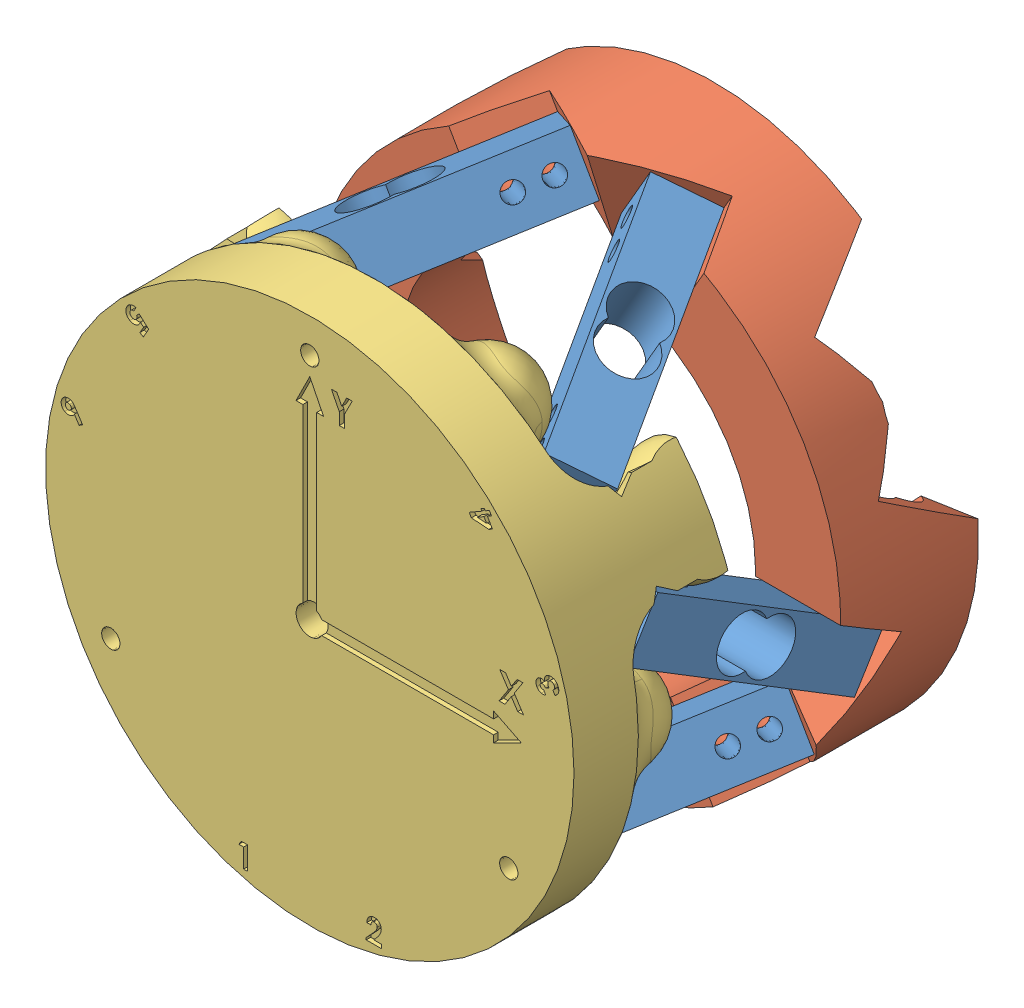
SolidWorks assembly Capteur 6 axes V3, configuration Défaut. Lengths in mm.
Overall size (115 115 88).
8 component instances, 3 part files, 19 mates.
Components (placement in the parent):
- Cellule_2kg-1: Cellule_2kg [Défaut] at (46.7654 0 44) x (1 0 0) z (0 -0.523016 -0.852323) size (12.7 12.7 58)
- Cellule_2kg-2: Cellule_2kg [Défaut] at (23.3827 40.5 44) x (0.5 0.866025 0) z (0.452945 -0.261508 0.852323) size (12.7 12.7 58)
- Cellule_2kg-3: Cellule_2kg [Défaut] at (-23.3827 40.5 44) x (0.5 -0.866025 0) z (-0.452945 -0.261508 0.852323) size (12.7 12.7 58)
- Cellule_2kg-4: Cellule_2kg [Défaut] at (-46.7654 0 44) x (1 0 0) z (0 -0.523016 -0.852323) size (12.7 12.7 58)
- Cellule_2kg-5: Cellule_2kg [Défaut] at (-23.3827 -40.5 44) x (0.5 0.866025 0) z (0.452945 -0.261508 0.852323) size (12.7 12.7 58)
- Cellule_2kg-6: Cellule_2kg [Défaut] at (23.3827 -40.5 44) x (0.5 -0.866025 0) z (-0.452945 -0.261508 0.852323) size (12.7 12.7 58)
- Bâti^Capteur 6 axes V3-1: Bâti^Capteur 6 axes V3 [Défaut] at origin size (115 115 30) (virtual)
- Socle^Capteur 6 axes V3-1: Socle^Capteur 6 axes V3 [Défaut] at origin size (115 115 36.74) (virtual)
Mates (geometry in assembly coordinates):
- Coïncidente1: coincident anti-aligned: line of Cellule_2kg-1 through (46.7654 16.9719 71.6579) axis (0 -0.523016 -0.852323); line of assembly
- Coïncidente2: coincident: point of Cellule_2kg-1; plane of assembly
- Coïncidente3: coincident anti-aligned: line of Cellule_2kg-2 through (8.6846 48.9859 16.3421) axis (0.452945 -0.261508 0.852323); line of assembly
- Coïncidente4: coincident: point of Cellule_2kg-2; plane of assembly
- Coïncidente5: coincident aligned: line of Cellule_2kg-3 through (-8.6846 48.9859 16.3421) axis (-0.452945 -0.261508 0.852323); line of assembly
- Coïncidente6: coincident: point of Cellule_2kg-3; plane of assembly
- Coïncidente7: coincident aligned: line of Cellule_2kg-4 through (-46.7654 16.9719 71.6579) axis (0 -0.523016 -0.852323); line of assembly
- Coïncidente8: coincident: point of Cellule_2kg-4; plane of assembly
- Coïncidente9: coincident aligned: line of Cellule_2kg-5 through (-38.0808 -32.0141 16.3421) axis (0.452945 -0.261508 0.852323); line of assembly
- Coïncidente10: coincident: point of Cellule_2kg-5; plane of assembly
- Coïncidente11: coincident anti-aligned: line of Cellule_2kg-6 through (38.0808 -32.0141 16.3421) axis (-0.452945 -0.261508 0.852323); line of assembly
- Coïncidente12: coincident: point of Cellule_2kg-6; plane of assembly
- Coïncidente15: coincident: line of Cellule_2kg-1 through (57.4904 0 44) axis (-1 0 0); point of assembly
- Coïncidente16: coincident: line of Cellule_2kg-2 through (28.7452 49.7881 44) axis (-0.5 -0.866025 0); point of assembly
- Coïncidente17: coincident: line of Cellule_2kg-3 through (-18.0202 31.2119 44) axis (-0.5 0.866025 0); point of assembly
- Coïncidente18: coincident: line of Cellule_2kg-4 through (-36.0404 0 44) axis (-1 0 0); point of assembly
- Coïncidente19: coincident: line of Cellule_2kg-5 through (-18.0202 -31.2119 44) axis (-0.5 -0.866025 0); point of assembly
- Coïncidente20: coincident: line of Cellule_2kg-6 through (28.7452 -49.7881 44) axis (-0.5 0.866025 0); point of assembly
- Coïncidente21: coordinate: point of Bâti^Capteur 6 axes V3-1; point of Socle^Capteur 6 axes V3-1
